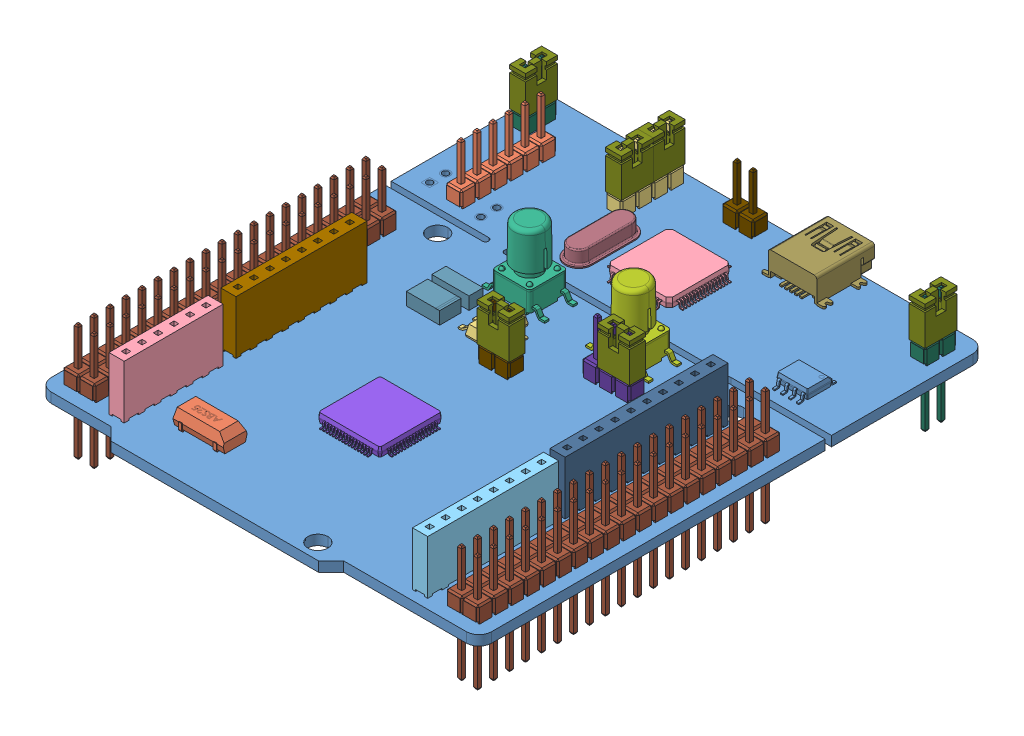
SolidWorks assembly NUCLEO-L476RG, configuration Défaut. Lengths in mm.
Overall size (70 20.7 83.95).
31 component instances, 22 part files, 0 mates.
Components (placement in the parent):
- NUCLEO-L476RG.step-1: NUCLEO-L476RG.step [Défaut] at origin size (70 20.7 83.95)
  - MB1136 rev C.step-1: MB1136 rev C.step [Défaut] at (0 0 25.42) size (70 1.58 82.5)
  - cn6.step-1: cn6.step [Défaut] at (-26.75 1.58 -19.65) x (0 0 -1) z (1 0 0) size (15.24 11.6 2.54)
  - cn4.step-1: cn4.step [Défaut] at (-12.75 1.58 -31.13) x (0 0 -1) z (1 0 0) size (10.16 11.6 2.54)
  - cn9.step-1: cn9.step [Défaut] at (-22.86 1.58 41.29) x (0 0 -1) z (1 0 0) size (15.75 11.57 2.41)
  - cn10.step-1: cn10.step [Défaut] at (22.86 1.58 38.75) x (0 0 -1) z (1 0 0) size (20.83 11.57 2.41)
  - b1.step-1: b1.step [Défaut] at (-8.2055 1.58 -12.0071) x (0 0 -1) z (1 0 0) size (6 10.7 10)
  - b2.step-1: b2.step [Défaut] at (8.3159 1.58 -12.0071) x (0 0 -1) z (1 0 0) size (6 10.7 10)
  - STM32lqfp64.step-1: STM32lqfp64.step [Défaut] at (-2.6807 2.3229 17.307) size (11.52 1.47 11.52)
  - cn8.step-1: cn8.step [Défaut] at (-22.86 1.58 9.54) x (0 0 -1) z (1 0 0) size (20.83 11.57 2.41)
  - cn7.step-1: cn7.step [Défaut] at (22.86 1.58 2.94) x (0 0 -1) z (1 0 0) size (25.91 11.57 2.41)
  - jp1 kon.step-1: jp1 kon.step [Défaut] at (-31.75 1.58 36.21) x (0 0 -1) z (1 0 0) size (48.26 18.54 5.08)
  - jp1 kon.step-2: jp1 kon.step [Défaut] at (29.21 1.58 36.21) x (0 0 -1) z (1 0 0) size (48.26 18.54 5.08)
  - cn1.step-1: cn1.step [Défaut] at (12.1 1.68 -40.94) x (-1 0 0) z (0 0 -1) size (10 5 9.5)
  - X1^NUCLEO-F401RE.step-1: X1^NUCLEO-F401RE.step [Défaut] at origin size (4.2 2.2 11.05)
  - additional^NUCLEO-F401RE.step-1: additional^NUCLEO-F401RE.step [Défaut] at origin size (5.92 2 6.62)
  - jp1.step-1: jp1.step [Défaut] at (-31.75 1.58 -37.45) x (0 0 1) z (-1 0 0) size (5.08 18.54 2.54)
  - jp1.step-2: jp1.step [Défaut] at (31.75 1.58 -37.45) x (0 0 1) z (-1 0 0) size (5.08 18.54 2.54)
  - Jumper 1.step-1: Jumper 1.step [Défaut] at (-31.75 4.12 -36.18) x (0 0 1) z (-1 0 0) size (5.08 6.1 2.54)
  - Jumper 1.step-2: Jumper 1.step [Défaut] at (31.75 4.12 -36.18) x (0 0 -1) z (1 0 0) size (5.08 6.1 2.54)
  - jp2_3 pin .step-1: jp2_3 pin .step [Défaut] at (13.3625 1.58 -6.3122) x (-1 0 0) z (0 0 -1) size (7.62 11.6 2.54)
  - jp2_2 pin.step-1: jp2_2 pin.step [Défaut] at (-1.95 1.58 0.05) size (5.08 11.6 2.54)
  - Jumper 1.step-3: Jumper 1.step [Défaut] at (-0.68 4.12 0.05) size (5.08 6.1 2.54)
  - Jumper 1.step-4: Jumper 1.step [Défaut] at (12.0925 4.12 -6.3122) size (5.08 6.1 2.54)
  - T2.step-1: T2.step [Défaut] at (26.0891 1.58 -21.4003) x (0 0 1) z (-1 0 0) size (6 1.75 4.9)
  - X2.step-1: X2.step [Défaut] at (-14.5189 2.9901 32.4903) x (-1 0 0) z (0 1 0) size (8 4 2.67)
  - L3.step-1: L3.step [Défaut] at (-5.8601 1.58 -4.4391) x (0 0 1) z (-1 0 0) size (6.5 1.8 7)
  - jp2_2 pin.step-2: jp2_2 pin.step [Défaut] at (-1.95 1.58 -38.75) size (5.08 11.6 2.54)
  - Jumper 1.step-5: Jumper 1.step [Défaut] at (-12.75 4.12 -32.4) x (0 0 -1) z (1 0 0) size (5.08 6.1 2.54)
  - Jumper 1.step-6: Jumper 1.step [Défaut] at (-12.75 4.12 -37.48) x (0 0 -1) z (1 0 0) size (5.08 6.1 2.54)
  - STM32F446RET6U.step-1: STM32F446RET6U.step [Défaut] at (0 2.455 -26) size (12 1.6 12)
